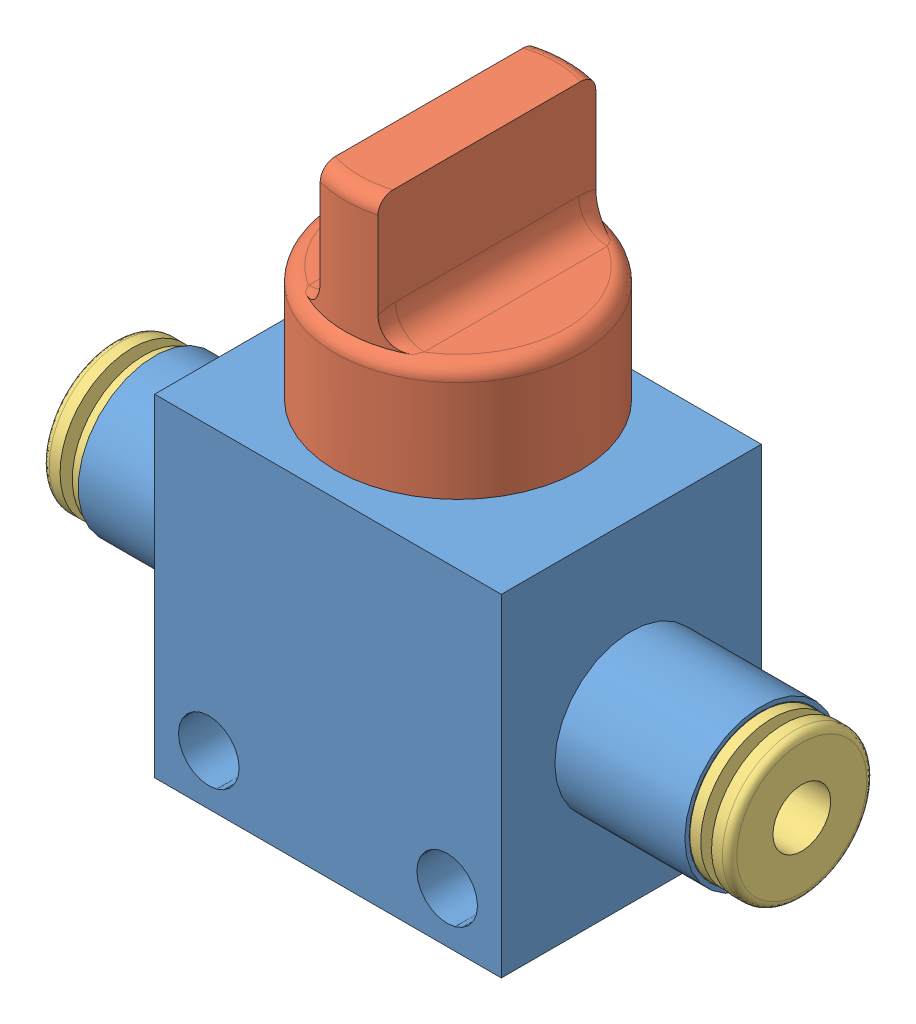
SolidWorks assembly On&Off Switch, configuration Default. Lengths in mm.
Overall size (47.6 41.02 23.22).
4 component instances, 3 part files, 9 mates.
Components (placement in the parent):
- Body^On&Off Switch-2: Body^On&Off Switch [Default] at (15.0144 18.8355 33.9353) size (42 24.2 18)
- Knob^On&Off Switch-1: Knob^On&Off Switch [Default] at (15.0144 32.0355 33.9353) x (-0.866025 0 -0.5) z (0.5 0 -0.866025) size (17 16.82 17)
- Fitting^On&Off Switch-1: Fitting^On&Off Switch [Default] at (23.0144 18.8355 33.9353) x (0 -0.8876 -0.460616) z (1 0 0) size (10 10 15.8)
- Fitting^On&Off Switch-2: Fitting^On&Off Switch [Default] at (7.0144 18.8355 33.9353) x (0 -0.990823 0.135164) z (-1 0 0) size (10 10 15.8)
Mates (geometry in assembly coordinates):
- Concentric1: concentric anti-aligned: cylinder of Body-2 through (23.0144 18.8355 33.9353) axis (-1 0 0) radius 5; cylinder of Fitting-1 through (36.0144 18.8355 33.9353) axis (1 0 0) radius 5
- Coincident1: coincident anti-aligned: plane of Body-2 through (23.0144 18.8355 33.9353) normal (1 0 0); plane of Fitting-1 through (23.0144 18.8355 33.9353) normal (-1 0 0)
- Concentric2: concentric anti-aligned: cylinder of Body-2 through (7.0144 18.8355 33.9353) axis (1 0 0) radius 5; cylinder of Fitting-2 through (-5.9856 18.8355 33.9353) axis (-1 0 0) radius 5
- Coincident2: coincident anti-aligned: plane of Body-2 through (7.0144 18.8355 33.9353) normal (-1 0 0); plane of Fitting-2 through (7.0144 18.8355 33.9353) normal (1 0 0)
- Concentric3: concentric aligned: circle of Body-2; cylinder of Knob^On&Off Switch-1 through (15.0144 40.0355 33.9353) axis (0 1 0) radius 8.5
- Coincident3: coincident anti-aligned: plane of Body-2 through (15.0144 32.0355 33.9353) normal (0 1 0); plane of Knob^On&Off Switch-1 through (15.0144 32.0355 33.9353) normal (0 -1 0)
- LimitAngle1: limit planar angle = 1.570796 rad aligned: plane of Body-2 through (3.0144 30.8355 42.9353) normal (0 0 1); plane of Knob-1 through (17.0144 48.8355 41.4745) normal (1 0 0)
- Parallel1: parallel aligned: plane of Copy of Body^On&Off Switch-2 through (3.0144 7.8355 42.9353) normal (-1 0 0); plane of Knob^On&Off Switch-1 through (13.0144 48.8355 41.4745) normal (-1 0 0)
- Parallel3: parallel aligned: plane of Copy of Body^On&Off Switch-2 through (3.0144 30.8355 24.9353) normal (0 0 -1); plane of Knob-1 through (7.4752 48.8355 31.9353) normal (0 0 -1)
